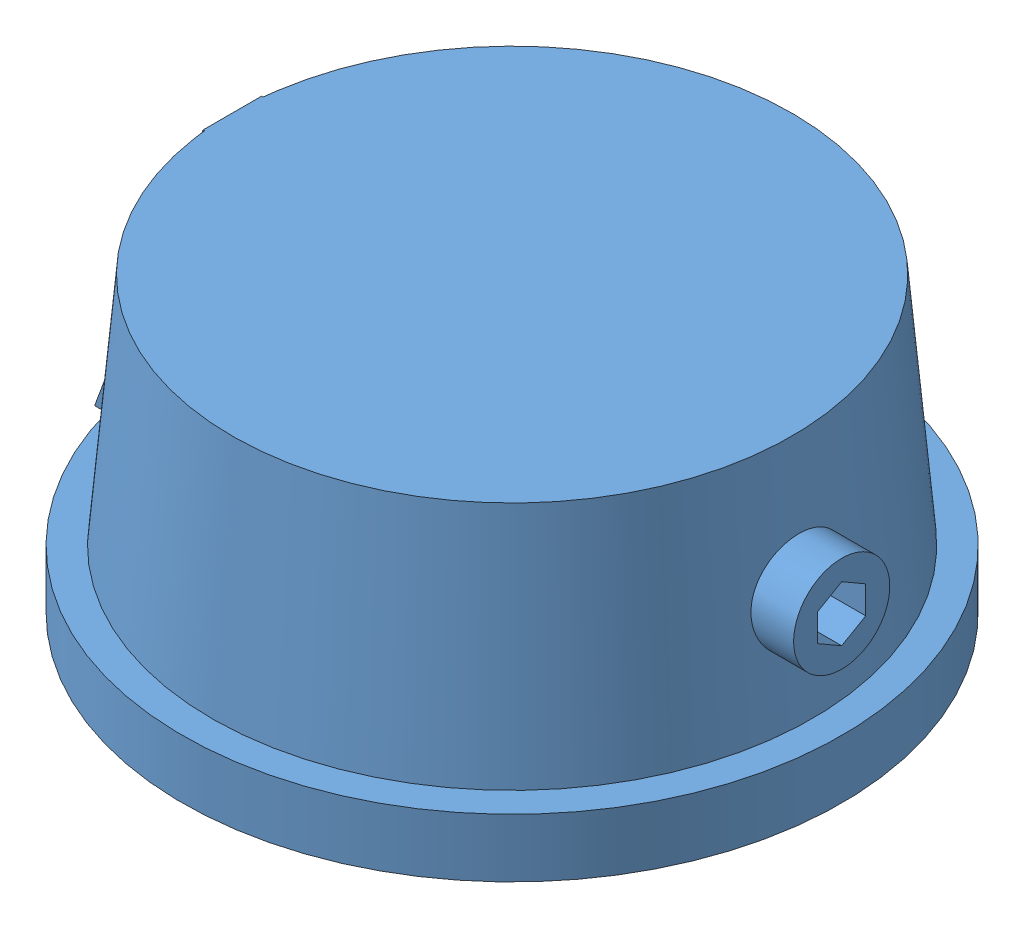
SolidWorks assembly EXTPRO-V1 22 VFD display & cable, configuration Default. Lengths in mm.
Overall size (22.7 9.19 14.29).
3 component instances, 1 part files, 1 mates.
Components (placement in the parent):
- EFC5610-3K00-3P4-MDA-XX-NNNNN-XXXX.stp-1: EFC5610-3K00-3P4-MDA-XX-NNNNN-XXXX.stp [Default] at origin
  - D_HOUSING_STO_1.stp-1: D_HOUSING_STO_1.stp [Default] at origin (suppressed, hidden)
- 6094K260_INDICATING KNOB-1: 6094K260_INDICATING KNOB [6094K26] at (31.9968 108.8235 17.8744) x (0 1 0) z (0 0 1) size (9.19 22.7 14.29)
Mates (geometry in assembly coordinates):
- Verrouiller1: lock: unknown of ?; unknown of 6094K260_INDICATING KNOB-1
